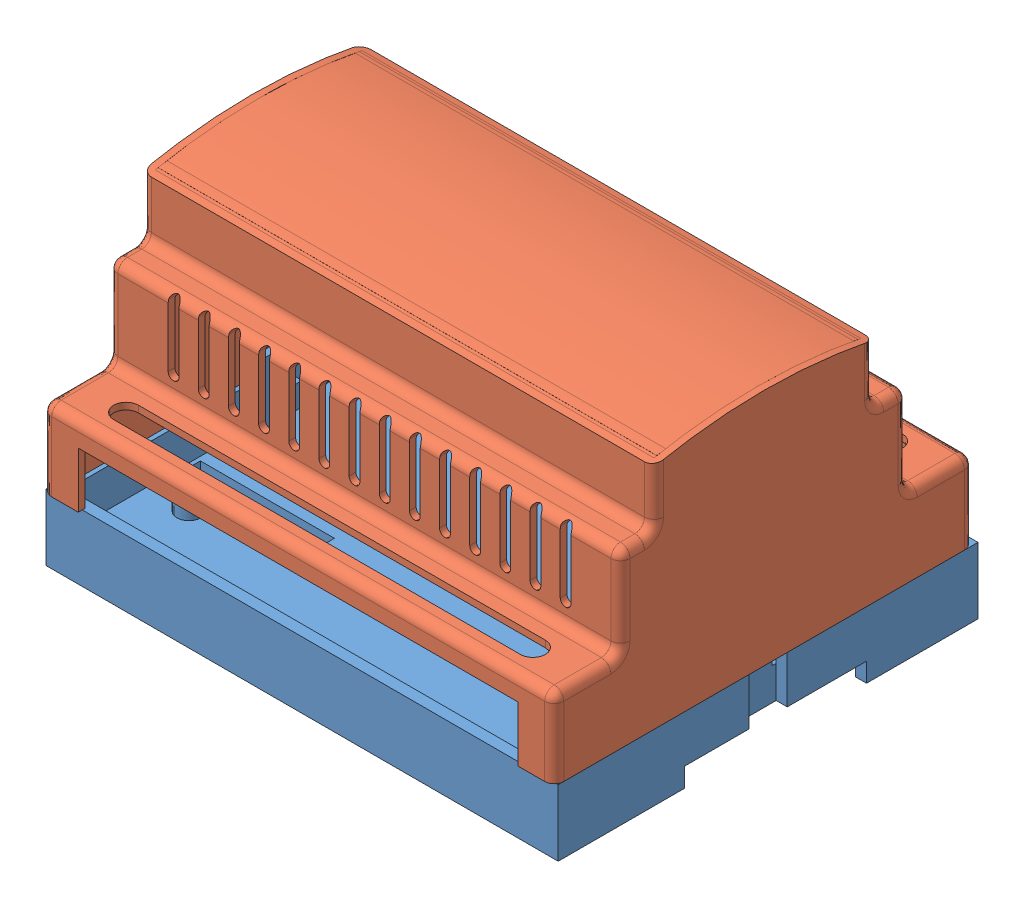
SolidWorks assembly Ensamblaje1, configuration Predeterminado. Lengths in mm.
Overall size (107 63.71 88.53).
2 component instances, 2 part files, 2 mates.
Components (placement in the parent):
- Base2017-1: Base2017 [Predeterminado] at (-7.1863 -3.1325 0) size (107 18.75 87.7)
- Tapa2017-1: Tapa2017 [Predeterminado] at (-7.1863 10.7175 0.8286) size (107 49.86 87.7)
Mates (geometry in assembly coordinates):
- Coincidente1: coincident anti-aligned: line of Base2017-1 through (46.3137 10.7175 4) axis (0 0 1); line of Tapa2017-1 through (46.3137 10.7175 42.6786) axis (0 0 -1)
- Coincidente2: coincident aligned: line of Base2017-1 through (-60.6863 10.7175 43.85) axis (0 0 -1); line of Tapa2017-1 through (-60.6863 10.7175 42.6786) axis (0 0 -1)
